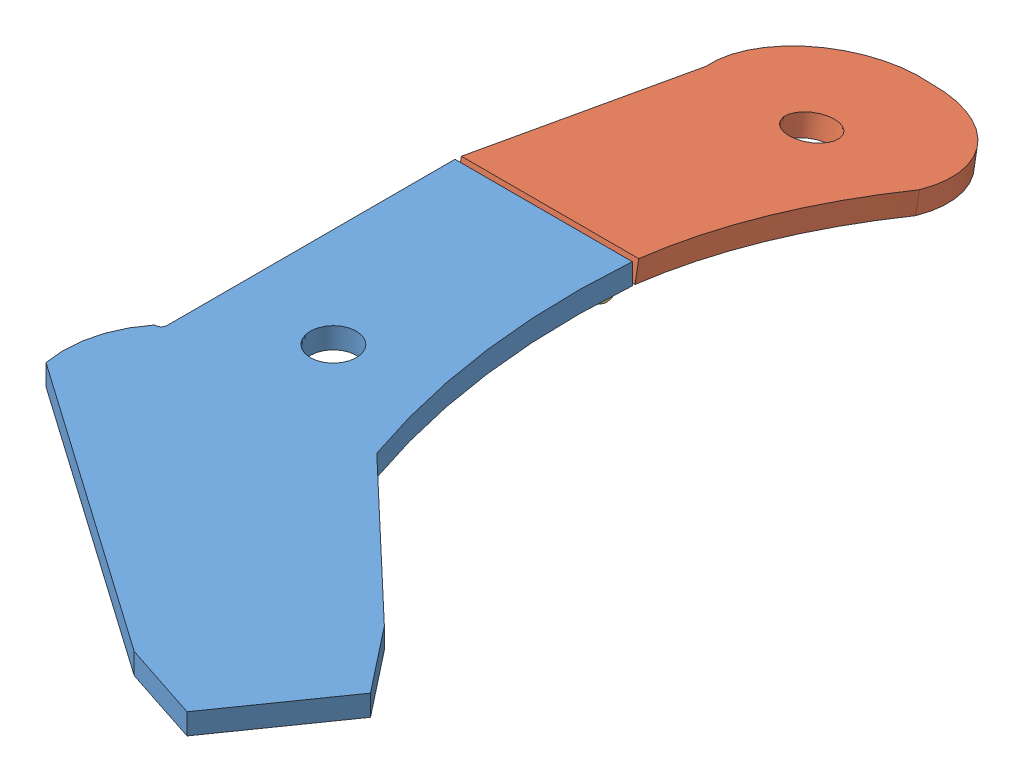
SolidWorks assembly LiftArmPaddleLeft, configuration Default. Lengths in mm.
Overall size (238.84 46.31 521.41).
4 component instances, 4 part files, 7 mates.
Components (placement in the parent):
- liftArmLower-1: liftArmLower [Default] at (0.282 201.1124 91.9918) size (238.84 11.11 324.8)
- liftArmUpper-1: liftArmUpper [Default] at (9.4101 177.4496 -39.0696) x (1 0 0) z (0 0.178618 0.983918) size (115.4 11.11 196.36)
- hingPart-1: hingPart [Default] at (33.1875 201.1124 124.9135) x (0 0 -1) z (-1 0 0) size (39.69 14.29 70.3)
- hingPartTwo-1: hingPartTwo [Default] at (-52.2089 196.4778 65.7471) x (0 -0.178618 -0.983918) z (-1 0 0) size (39.69 14.29 67.07)
Mates (geometry in assembly coordinates):
- Coincident2: coincident aligned: circle of hingPart-1; circle of hingPartTwo-1
- Coincident14: coincident anti-aligned: plane of liftArmLower-1 through (-49.9227 201.1124 244.5902) normal (0 -1 0); plane of hingPart-1 through (33.1875 201.1124 124.9135) normal (0 1 0)
- Coincident15: coincident anti-aligned: line of liftArmLower-1 through (47.3117 201.1124 91.9918) axis (-1 0 0); line of hingPart-1 through (-36.5877 201.1124 91.9918) axis (1 0 0)
- Coincident16: coincident anti-aligned: plane of liftArmUpper-1 through (3.7577 175.2065 -51.4259) normal (0 -0.983918 0.178618); plane of hingPartTwo-1 through (-52.2089 196.4778 65.7471) normal (0 0.983918 -0.178618)
- Coincident17: coincident anti-aligned: line of liftArmUpper-1 through (-46.7477 200.9848 90.574) axis (1 0 0); line of hingPartTwo-1 through (32.1248 200.9848 90.574) axis (-1 0 0)
- Coincident18: coincident aligned: plane of liftArmLower-1 through (-46.7477 212.2249 91.9918) normal (-1 0 0); plane of liftArmUpper-1 through (-46.7477 188.3834 -41.0545) normal (-1 0 0)
- Distance2: distance = 10.16 mm aligned: plane of hingPart-1 through (-36.5877 201.1124 124.9135) normal (-1 0 0); plane of liftArmLower-1 through (-46.7477 212.2249 91.9918) normal (-1 0 0)
